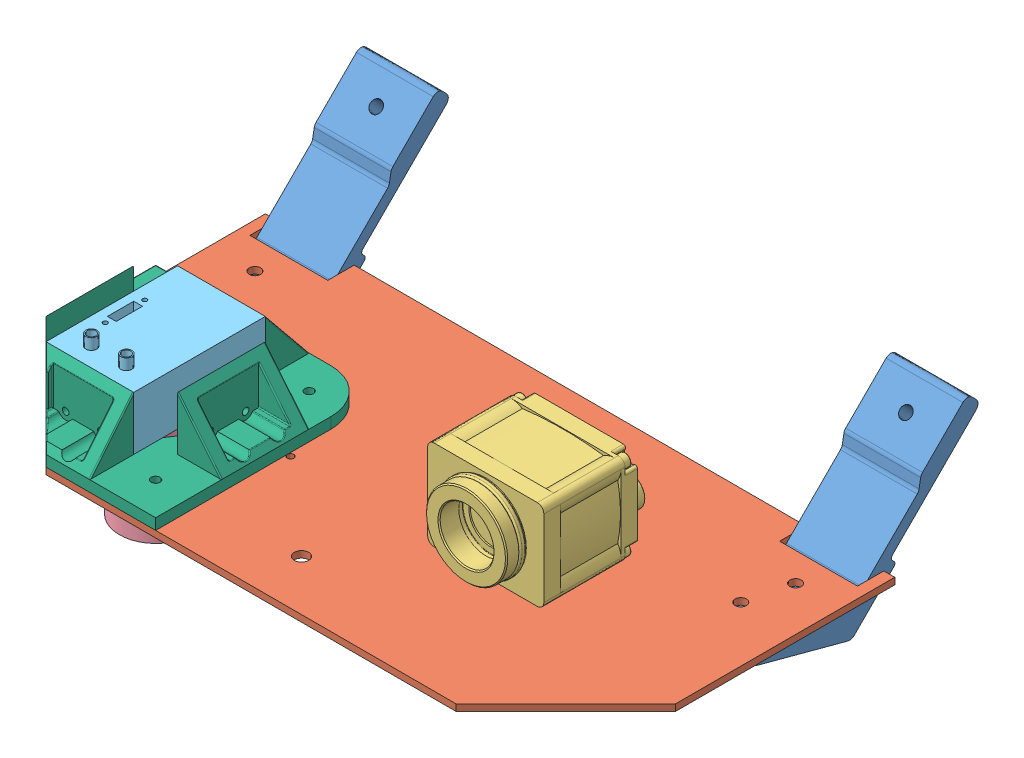
SolidWorks assembly CameraMountPlate, configuration Default. Lengths in mm.
Overall size (287.02 92.63 193.19).
8 component instances, 6 part files, 13 mates.
Components (placement in the parent):
- Bracket-1: Bracket [Default] at (-10.8339 54.0228 74.591) size (35 68.99 103.19)
- Plate-1: Plate [Default] at (270.9161 45.0124 233.6725) x (-1 0 0) z (0 -1 0) size (287 150 3)
- UI-5260FA-C-HQ-1: UI-5260FA-C-HQ [Default] at (177.4161 65.5124 176.6725) size (53 41 63.3)
- DAVIS346-1: DAVIS346 [Default] at (10.3261 26.7228 66.0845) x (-0.644351 0 -0.76473) z (-0.76473 0 0.644351) size (71.66 78 69.25)
  - DAVIS346_lens-1: DAVIS346_lens [Default] at (-105.1233 -22.2896 57.728) size (41 51.5 41)
  - DAVIS346-1: DAVIS346 [Default] at (-69.2944 -23.2896 53.692) x (-0.76473 0 0.644351) z (0 -1 0) size (60 40 30.5)
- Bracket-2: Bracket [Default] at (230.6661 54.0228 74.591) size (35 68.99 103.19)
- Davis346VerticalBracket-1: Davis346VerticalBracket [Default] at (33.9161 45.0124 183.6725) size (100.02 29.5 100.02)
Mates (geometry in assembly coordinates):
- Concentric10: concentric aligned: cylinder of Bracket-1 through (9.1661 24.812 128.6725) axis (0 1 0) radius 2.75; cylinder of Plate-1 through (9.1661 42.0124 128.6725) axis (0 1 0) radius 2.6
- Coincident5: coincident anti-aligned: plane of Bracket-1 through (24.1661 42.0124 93.6725) normal (0 1 0); plane of Plate-1 through (270.9161 42.0124 233.6725) normal (0 -1 0)
- Parallel8: parallel: line of Bracket-1 through (24.1661 93.2672 47.3674) axis (-1 0 0); plane of Plate-1 through (-11.0839 42.0124 95.6725) normal (0 0 -1)
- Concentric12: concentric anti-aligned: cylinder of Plate-1 through (177.4161 42.0124 136.9725) axis (0 1 0) radius 2.2; cylinder of UI-5260FA-C-HQ-1 through (177.4161 45.0124 136.9725) axis (0 -1 0) radius 2.1
- Coincident8: coincident aligned: circle of Plate-1; cylinder of UI-5260FA-C-HQ-1 through (160.9161 45.0124 173.6725) axis (0 -1 0) radius 2.1
- Coincident9: coincident anti-aligned: plane of Plate-1 through (270.9161 45.0124 233.6725) normal (0 1 0); plane of UI-5260FA-C-HQ-1 through (153.9161 45.0124 169.1725) normal (0 -1 0)
- Parallel9: parallel anti-aligned: plane of Plate-1 through (270.9161 45.0124 233.6725) normal (0 1 0); plane of DAVIS346-1/DAVIS346-1 through (13.9161 50.0124 153.6725) normal (0 -1 0)
- Parallel11: parallel: line of Plate-1 through (-16.0839 42.0124 183.6725) axis (0 0 -1); plane of DAVIS346-1/DAVIS346-1 through (13.9161 74.5124 153.6725) normal (-1 0 0)
- Concentric16: concentric aligned: cylinder of Plate-1 through (33.9161 42.0124 183.6725) axis (0 1 0) radius 26; cylinder of DAVIS346-1/DAVIS346_lens-1 through (33.9161 1.5124 183.6725) axis (0 1 0) radius 16.5
- Distance1: distance = 5 mm anti-aligned: plane of DAVIS346-1/DAVIS346-1 through (13.9161 50.0124 153.6725) normal (0 -1 0); plane of Plate-1 through (270.9161 45.0124 233.6725) normal (0 1 0)
- Coincident13: coincident: circle of Plate-1; cylinder of Davis346VerticalBracket-1 through (33.9161 50.0124 183.6725) axis (0 -1 0) radius 26
- Parallel12: parallel: plane of Plate-1 through (220.9161 42.0124 233.6725) normal (0 0 1); plane of Davis346VerticalBracket-1 through (220.9161 42.0124 233.6725) normal (0 0 1)
- Coincident15: coincident anti-aligned: plane of Plate-1 through (270.9161 45.0124 233.6725) normal (0 1 0); plane of Davis346VerticalBracket-1 through (33.9161 45.0124 183.6725) normal (0 -1 0)
